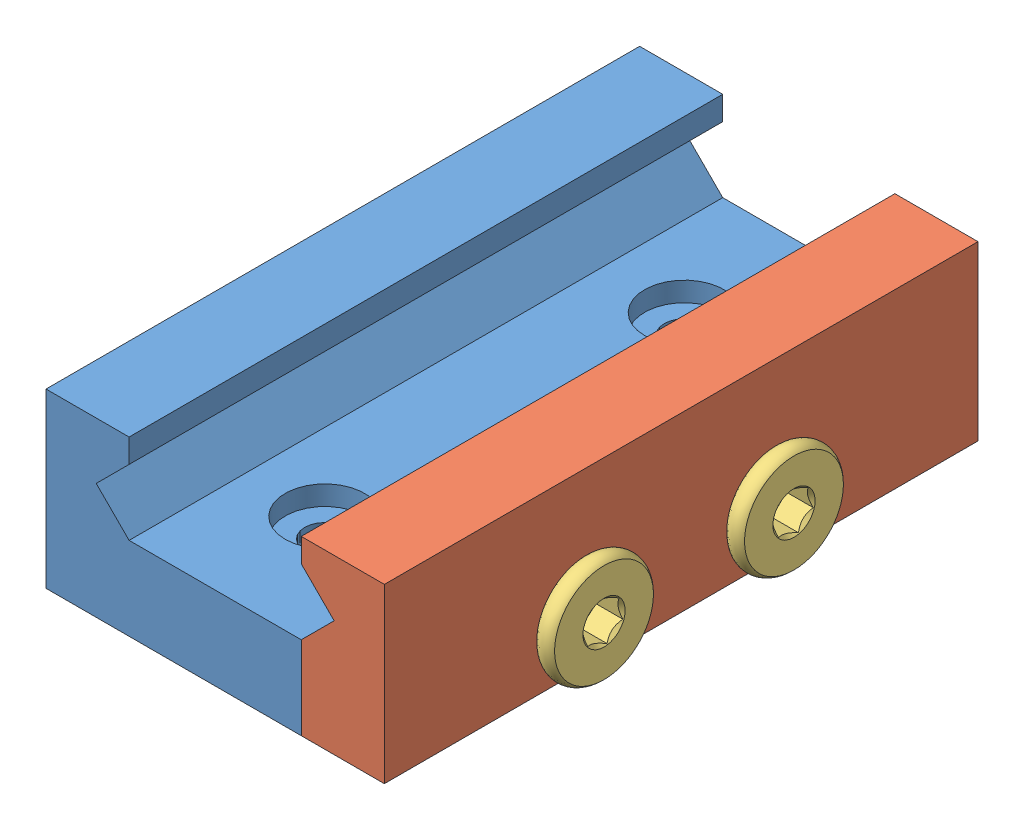
SolidWorks assembly laser mout all, configuration Default. Lengths in mm.
Overall size (36.62 16.3 50).
4 component instances, 3 part files, 9 mates.
Components (placement in the parent):
- laser mount right base-1: laser mount right base [Default] at (46.0139 7.6407 36.483) size (21.5 14.54 50)
- laser mount left base-1: laser mount left base [Default] at (29.0869 7.6407 86.483) x (-1 0 0) z (0 0 -1) size (7 14.54 50)
- Low Profile Screw M5-1: Low Profile Screw M5 [M5 x 35] at (16.8004 62.7378 69.483) x (-1 0 0) z (0 0.940544 -0.339673) size (36.62 9 9)
- Low Profile Screw M5-2: Low Profile Screw M5 [M5 x 35] at (16.8004 62.7378 53.483) x (-1 0 0) z (0 -0.962482 0.271347) size (36.62 9 9)
Mates (geometry in assembly coordinates):
- Coincident1: coincident aligned: plane of laser mount right base-1 through (44.8004 58.7378 86.483) normal (0 -1 0); plane of laser mount left base-1 through (44.8004 58.7378 36.483) normal (0 -1 0)
- Coincident2: coincident aligned: plane of laser mount right base-1 through (46.0139 7.6407 86.483) normal (0 0 1); plane of laser mount left base-1 through (29.0869 7.6407 86.483) normal (0 0 1)
- Screw2: screw = 1 aligned: cylinder of laser mount right base-1 through (44.8014 62.7378 53.483) axis (-1 0 0) radius 2.5; cylinder of Low Profile Screw M5-2 through (51.8004 62.7378 53.483) axis (-1 0 0) radius 2.5
- Concentric2: concentric anti-aligned: cylinder of laser mount left base-1 through (44.7994 62.7378 53.483) axis (1 0 0) radius 2.5; cylinder of Low Profile Screw M5-2 through (51.8004 62.7378 53.483) axis (-1 0 0) radius 2.5
- Coincident3: coincident anti-aligned: plane of laser mount left base-1 through (51.8004 58.7378 36.483) normal (1 0 0); plane of Low Profile Screw M5-2 through (51.8004 61.6087 49.4777) normal (-1 0 0)
- Screw3: screw = 1 aligned: cylinder of laser mount right base-1 through (44.8014 62.7378 69.483) axis (-1 0 0) radius 2.5; cylinder of Low Profile Screw M5-1 through (51.8004 62.7378 69.483) axis (-1 0 0) radius 2.5
- Concentric3: concentric anti-aligned: cylinder of laser mount left base-1 through (44.7994 62.7378 69.483) axis (1 0 0) radius 2.5; cylinder of Low Profile Screw M5-1 through (51.8004 62.7378 69.483) axis (-1 0 0) radius 2.5
- Coincident4: coincident anti-aligned: plane of laser mount left base-1 through (51.8004 58.7378 36.483) normal (1 0 0); plane of Low Profile Screw M5-1 through (51.8004 64.1514 73.397) normal (-1 0 0)
- LimitDistance1: limit distance = 0 mm anti-aligned: plane of laser mount left base-1 through (44.8004 65.7378 36.483) normal (-1 0 0); plane of laser mount right base-1 through (44.8004 65.7378 86.483) normal (1 0 0)
